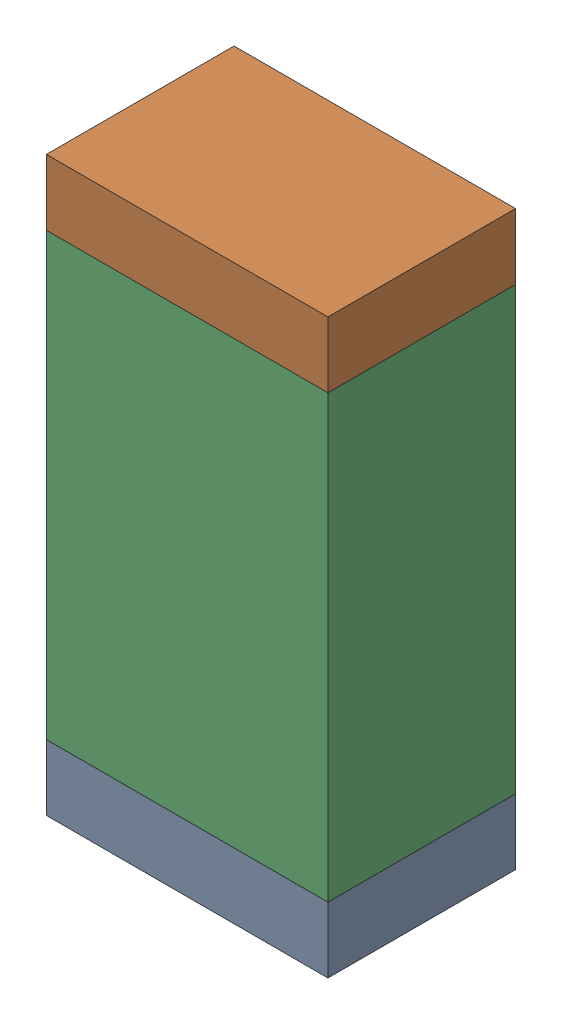
SolidWorks assembly R1, configuration Default. Lengths in mm.
Overall size (0.76 1.55 0.51).
6 component instances, 2 part files, 0 mates.
Components (placement in the parent):
- 822501776-1: 822501776 [Default] at (22.8602 4.7245 0) size (0.76 0.18 0.51)
  - Extruded_3-1: Extruded_3 [Default] at origin size (0.76 0.18 0.51)
- 822501776-2: 822501776 [Default] at (22.8602 6.0961 0) size (0.76 0.18 0.51)
  - Extruded_3-1: Extruded_3 [Default] at origin size (0.76 0.18 0.51)
- 822501912-1: 822501912 [Default] at (22.8602 5.4103 0) size (0.76 1.19 0.51)
  - Extruded_4-1: Extruded_4 [Default] at origin size (0.76 1.19 0.51)
